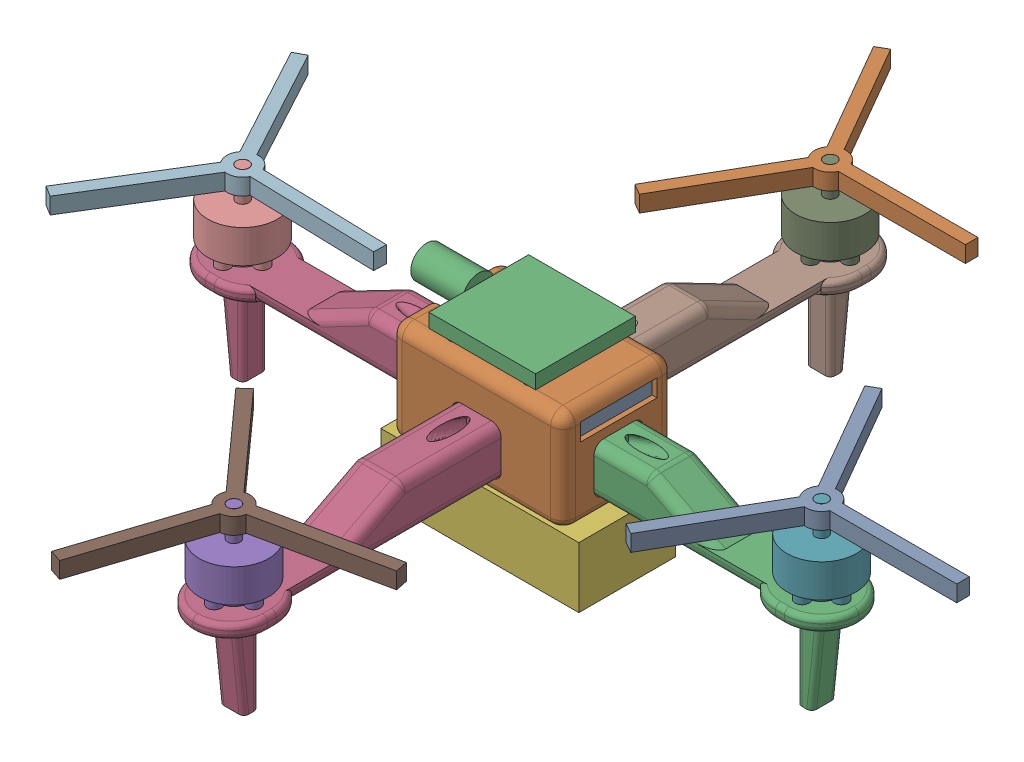
SolidWorks assembly Drone_Asm, configuration Default. Lengths in mm.
Overall size (323.32 81.44 347.79).
16 component instances, 8 part files, 52 mates.
Components (placement in the parent):
- 1S Battery-1: 1S Battery [Default] at (-11.5324 16.3151 26.293) size (53 6.5 30.2)
- Drone_Body_v2-1: Drone_Body_v2 [Default] at (-18.0324 -12.1849 26.693) x (-1 0 0) z (0 0 -1) size (70 40 45)
- ESC-1: ESC [Default] at (-18.0324 30.1951 26.693) size (64.1 13 40.3)
- Drone_Arm-1: Drone_Arm [Default] at (-18.0324 2.8151 46.193) x (0 0 1) z (-1 0 0) size (117.5 54.5 30)
- Motor-1: Motor [Default] at (-18.0324 4.1651 147.193) size (28 31.2 28)
- 4S Battery-2: 4S Battery [Default] at (-16.658 -36.6849 29.693) size (80 24.5 39)
- Motor-2: Motor [Default] at (98.9676 4.1651 26.693) size (28 31.2 28)
- Drone_Arm-3: Drone_Arm [Default] at (-18.0324 2.8151 7.193) x (0 0 -1) z (1 0 0) size (117.5 54.5 30)
- Motor-3: Motor [Default] at (-18.0324 4.1651 -93.807) x (0 0 -1) z (1 0 0) size (28 31.2 28)
- Motor-4: Motor [Default] at (-135.0324 4.1651 26.693) x (-1 0 0) z (0 0 -1) size (28 31.2 28)
- 4x4E-3-1: 4x4E-3 [Default] at (-18.0324 23.1611 147.193) x (0.978437 0 -0.206547) z (0.206547 0 0.978437) size (87.92 6.6 101.53)
- 4x4E-3-2: 4x4E-3 [Default] at (-135.0324 23.1611 26.693) x (0.999616 0 0.027696) z (-0.027696 0 0.999616) size (87.92 6.6 101.53)
- 4x4E-3-3: 4x4E-3 [Default] at (98.9676 23.1611 26.693) size (87.92 6.6 101.53)
- 4x4E-3-4: 4x4E-3 [Default] at (-18.0324 23.1611 -93.807) size (87.92 6.6 101.53)
- Drone_Arm_Short-1: Drone_Arm_Short [Default] at (13.9676 2.8151 26.693) size (100 54.5 30)
- Drone_Arm_Short-2: Drone_Arm_Short [Default] at (-50.0324 2.8151 26.693) x (-1 0 0) z (0 0 -1) size (100 54.5 30)
Mates (geometry in assembly coordinates):
- Concentric5: concentric aligned: circle of Drone_Body_v2-1; circle of ESC-1
- Concentric6: concentric aligned: circle of Drone_Body_v2-1; circle of ESC-1
- Coincident2: coincident anti-aligned: plane of Drone_Body_v2-1 through (-18.0324 27.8151 26.693) normal (0 1 0); plane of ESC-1 through (-33.2824 27.8151 11.443) normal (0 -1 0)
- Coincident3: coincident anti-aligned: plane of 1S Battery-1 through (-38.0324 22.8151 41.393) normal (-1 0 0); plane of Drone_Body_v2-1 through (-38.0324 -12.1849 26.693) normal (1 0 0)
- Coincident4: coincident anti-aligned: plane of 1S Battery-1 through (-38.0324 22.8151 11.193) normal (0 0 -1); plane of Drone_Body_v2-1 through (-38.0324 16.3151 11.193) normal (0 0 1)
- Coincident5: coincident anti-aligned: plane of 1S Battery-1 through (-11.5324 16.3151 26.293) normal (0 -1 0); plane of Drone_Body_v2-1 through (-38.0324 16.3151 42.193) normal (0 1 0)
- Coincident6: coincident anti-aligned: plane of Drone_Body_v2-1 through (-24.0324 -3.1849 46.193) normal (0 0 1); plane of Drone_Arm-1 through (-23.7824 -2.9349 46.193) normal (0 0 -1)
- Concentric7: concentric anti-aligned: circle of Drone_Arm-1; circle of Motor-1
- Concentric8: concentric anti-aligned: circle of Drone_Arm-1; circle of Motor-1
- Coincident7: coincident anti-aligned: plane of Drone_Arm-1 through (-3.0324 -1.4349 163.693) normal (0 1 0); plane of Motor-1 through (-18.0324 -1.4349 147.193) normal (0 -1 0)
- Coincident8: coincident anti-aligned: plane of Drone_Body_v2-1 through (-18.0324 -12.1849 26.693) normal (0 -1 0); plane of 4S Battery-2 through (-16.658 -12.1849 29.693) normal (0 1 0)
- Coincident10: coincident aligned: plane of Drone_Body_v2-1 through (16.9676 27.8151 49.193) normal (0 0 1); plane of 4S Battery-2 through (-56.658 -12.1849 49.193) normal (0 0 1)
- Concentric9: concentric anti-aligned: circle of Drone_Body_v2-1; circle of Drone_Arm-1
- Concentric10: concentric aligned: circle of Drone_Body_v2-1; circle of Drone_Arm-1
- Concentric11: concentric aligned: circle of Drone_Body_v2-1; circle of Drone_Arm-2
- Concentric12: concentric anti-aligned: circle of Drone_Body_v2-1; circle of Drone_Arm-2
- Coincident15: coincident anti-aligned: plane of Drone_Body_v2-1 through (13.9676 -3.1849 20.693) normal (1 0 0); plane of Drone_Arm-2 through (13.9676 -2.9349 32.443) normal (-1 0 0)
- Concentric13: concentric anti-aligned: circle of Drone_Arm-2; circle of Motor-2
- Concentric14: concentric anti-aligned: circle of Drone_Arm-2; circle of Motor-2
- Coincident16: coincident anti-aligned: plane of Drone_Arm-2 through (131.4676 -1.4349 11.693) normal (0 1 0); plane of Motor-2 through (98.9676 -1.4349 26.693) normal (0 -1 0)
- Concentric15: concentric anti-aligned: circle of Drone_Arm-3; circle of Motor-3
- Concentric16: concentric anti-aligned: circle of Drone_Arm-3; circle of Motor-3
- Coincident17: coincident anti-aligned: plane of Drone_Arm-3 through (-33.0324 -1.4349 -110.307) normal (0 1 0); plane of Motor-3 through (-18.0324 -1.4349 -93.807) normal (0 -1 0)
- Concentric17: concentric aligned: circle of Drone_Body_v2-1; circle of Drone_Arm-3
- Concentric18: concentric anti-aligned: circle of Drone_Body_v2-1; circle of Drone_Arm-3
- Coincident20: coincident anti-aligned: plane of Drone_Body_v2-1 through (-24.0324 -3.1849 7.193) normal (0 0 -1); plane of Drone_Arm-3 through (-12.2824 -2.9349 7.193) normal (0 0 1)
- Concentric19: concentric anti-aligned: circle of Drone_Arm-4; circle of Motor-4
- Concentric20: concentric anti-aligned: circle of Drone_Arm-4; circle of Motor-4
- Coincident21: coincident anti-aligned: plane of Drone_Arm-4 through (-167.5324 -1.4349 41.693) normal (0 1 0); plane of Motor-4 through (-135.0324 -1.4349 26.693) normal (0 -1 0)
- Concentric21: concentric anti-aligned: circle of Drone_Body_v2-1; circle of Drone_Arm-4
- Concentric22: concentric aligned: circle of Drone_Body_v2-1; circle of Drone_Arm-4
- Coincident24: coincident anti-aligned: plane of Drone_Body_v2-1 through (-50.0324 -3.1849 20.693) normal (-1 0 0); plane of Drone_Arm-4 through (-50.0324 -2.9349 20.943) normal (1 0 0)
- Concentric23: concentric aligned: circle of Motor-3; circle of 4x4E-3-4
- Coincident25: coincident aligned: plane of Motor-3 through (-18.0324 29.7651 -93.807) normal (0 1 0); plane of 4x4E-3-4 through (-18.0324 29.7651 -93.807) normal (0 1 0)
- Concentric24: concentric aligned: circle of Motor-4; circle of 4x4E-3-2
- Coincident26: coincident aligned: plane of Motor-4 through (-135.0324 29.7651 26.693) normal (0 1 0); plane of 4x4E-3-2 through (-135.0324 29.7651 26.693) normal (0 1 0)
- Concentric25: concentric aligned: circle of Motor-2; circle of 4x4E-3-3
- Coincident27: coincident aligned: plane of Motor-2 through (98.9676 29.7651 26.693) normal (0 1 0); plane of 4x4E-3-3 through (98.9676 29.7651 26.693) normal (0 1 0)
- Concentric26: concentric aligned: circle of Motor-1; circle of 4x4E-3-1
- Coincident28: coincident aligned: plane of Motor-1 through (-18.0324 29.7651 147.193) normal (0 1 0); plane of 4x4E-3-1 through (-18.0324 29.7651 147.193) normal (0 1 0)
- Concentric27: concentric aligned: circle of Drone_Body_v2-1; circle of Drone_Arm_Short-1
- Concentric28: concentric anti-aligned: circle of Drone_Body_v2-1; circle of Drone_Arm_Short-1
- Coincident31: coincident anti-aligned: plane of Drone_Body_v2-1 through (13.9676 -3.1849 20.693) normal (1 0 0); plane of Drone_Arm_Short-1 through (13.9676 -2.9349 32.443) normal (-1 0 0)
- Concentric29: concentric anti-aligned: circle of Motor-2; circle of Drone_Arm_Short-1
- Concentric30: concentric anti-aligned: circle of Motor-2; circle of Drone_Arm_Short-1
- Coincident32: coincident anti-aligned: plane of Motor-2 through (98.9676 -1.4349 26.693) normal (0 -1 0); plane of Drone_Arm_Short-1 through (113.9676 -1.4349 11.693) normal (0 1 0)
- Concentric31: concentric anti-aligned: circle of Drone_Body_v2-1; circle of Drone_Arm_Short-2
- Concentric32: concentric aligned: circle of Drone_Body_v2-1; circle of Drone_Arm_Short-2
- Coincident35: coincident anti-aligned: plane of Drone_Body_v2-1 through (-50.0324 -3.1849 20.693) normal (-1 0 0); plane of Drone_Arm_Short-2 through (-50.0324 -2.9349 20.943) normal (1 0 0)
- Concentric33: concentric anti-aligned: circle of Motor-4; circle of Drone_Arm_Short-2
- Concentric34: concentric anti-aligned: circle of Motor-4; circle of Drone_Arm_Short-2
- Coincident36: coincident anti-aligned: plane of Motor-4 through (-135.0324 -1.4349 26.693) normal (0 -1 0); plane of Drone_Arm_Short-2 through (-150.0324 -1.4349 41.693) normal (0 1 0)
